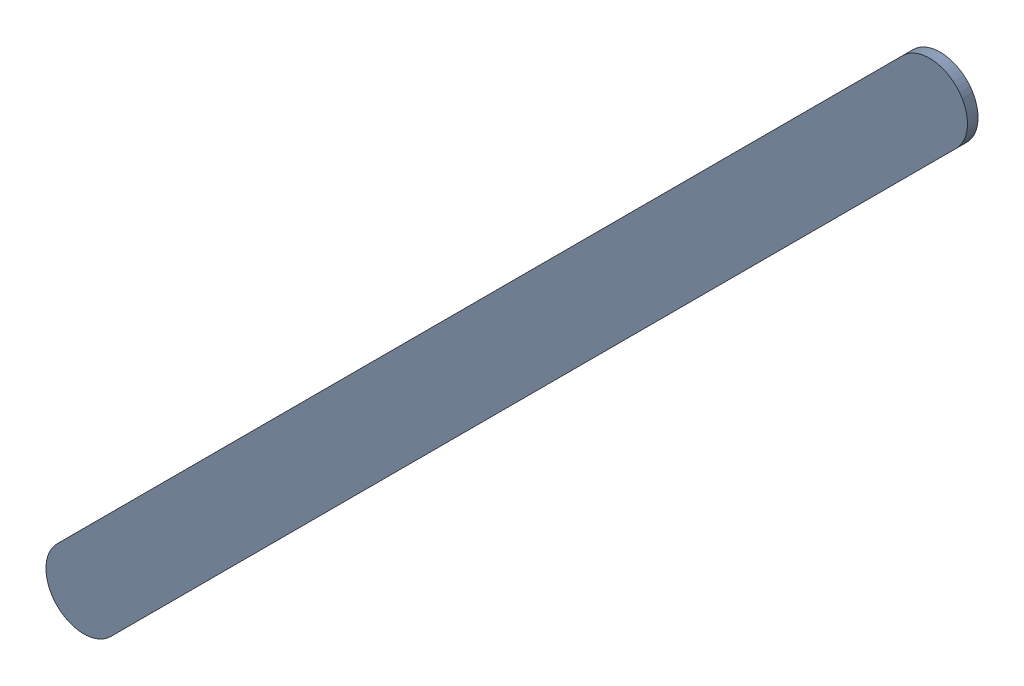
SolidWorks assembly Track (26.366mm,6.3mm)(29.2mm,9.134mm) on Top Layer, configuration Predeterminado. Lengths in mm.
Overall size (3.09 3.09 0.04).
2 component instances, 1 part files, 0 mates.
Components (placement in the parent):
- Track (26.366mm,6.3mm)(29.2mm,9.134mm) on Top Layer-1-1: Track (26.366mm,6.3mm)(29.2mm,9.134mm) on Top Layer-1 [Predeterminado] at (-68.317 -44.187 -0.0457) size (3.09 3.09 0.04)
  - Track (26.366mm,6.3mm)(29.2mm,9.134mm) on Top Layer-Part-1-1: Track (26.366mm,6.3mm)(29.2mm,9.134mm) on Top Layer-Part-1 [Predeterminado] at origin size (3.09 3.09 0.04)
